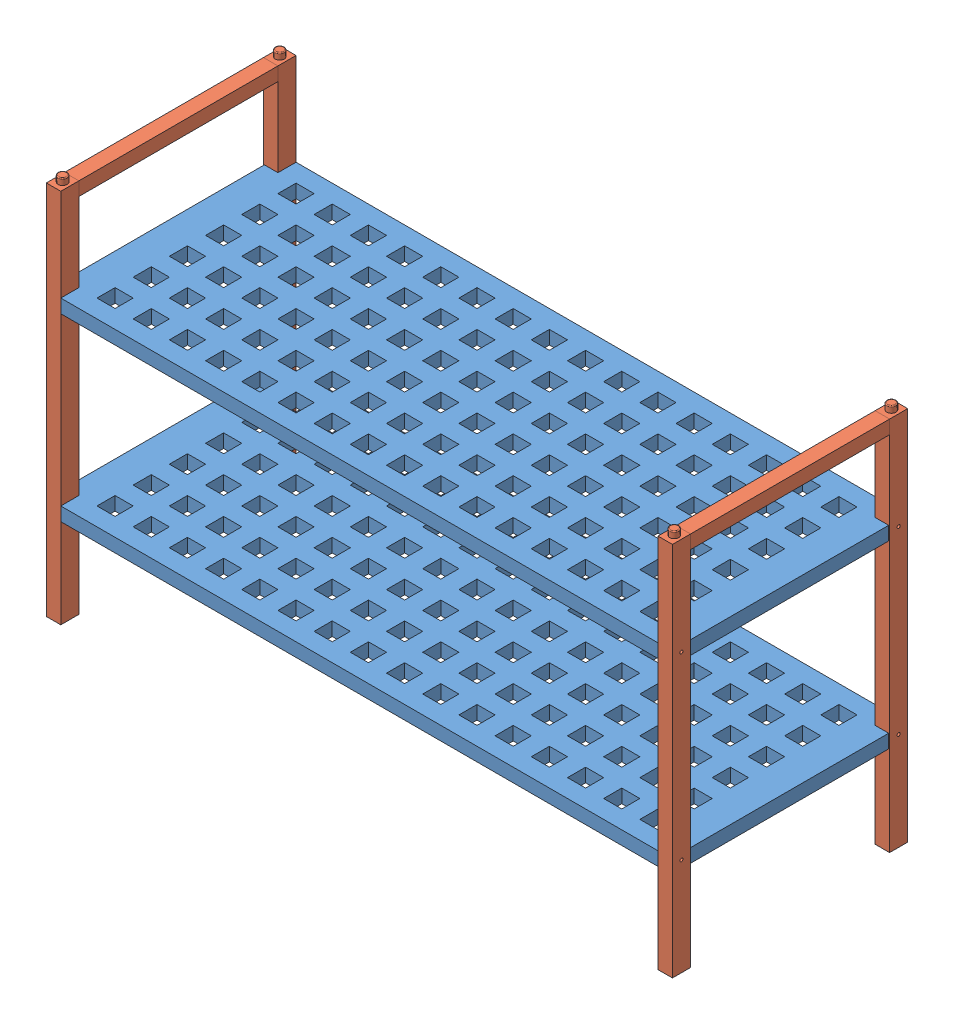
SolidWorks assembly Shoe Rack Assembly - Homework 2, configuration Default. Lengths in mm.
Overall size (692 422 260).
4 component instances, 2 part files, 13 mates.
Components (placement in the parent):
- Shoe Rack Plate - Homework 2-1: Shoe Rack Plate - Homework 2 [Default] at origin size (690 15 260)
- Shoe Rack End - Homework 2-2: Shoe Rack End - Homework 2 [Default] at (-374.3767 -95.0019 -133.8437) x (0 0 1) z (-1 0 0) size (260 422 16)
- Shoe Rack End - Homework 2-3: Shoe Rack End - Homework 2 [Default] at (317.6233 -95.0019 86.1563) x (0 0 -1) z (1 0 0) size (260 422 16)
- Shoe Rack Plate - Homework 2-4: Shoe Rack Plate - Homework 2 [Default] at (0 -199 0) size (690 15 260)
Mates (geometry in assembly coordinates):
- Coincident6: coincident anti-aligned: plane of Shoe Rack Plate - Homework 2-1 through (-358.3767 -15 -133.8437) normal (-1 0 0); plane of Shoe Rack End - Homework 2-2 through (-358.3767 -312.8 -153.8437) normal (1 0 0)
- Coincident7: coincident anti-aligned: plane of Shoe Rack Plate - Homework 2-1 through (-373.3767 -15 -133.8437) normal (0 0 -1); plane of Shoe Rack End - Homework 2-2 through (-374.3767 -95.0019 -133.8437) normal (0 0 1)
- Coincident8: coincident: circle of assembly; point of Shoe Rack Plate - Homework 2-1; circle of Shoe Rack End - Homework 2-2
- Coincident10: coincident anti-aligned: plane of Shoe Rack Plate - Homework 2-1 through (301.6233 -15 86.1563) normal (1 0 0); plane of Shoe Rack End - Homework 2-3 through (301.6233 -312.8 106.1563) normal (-1 0 0)
- Coincident11: coincident anti-aligned: plane of Shoe Rack Plate - Homework 2-1 through (316.6233 -15 86.1563) normal (0 0 1); plane of Shoe Rack End - Homework 2-3 through (317.6233 -95.0019 86.1563) normal (0 0 -1)
- Coincident12: coincident: circle of assembly; point of Shoe Rack Plate - Homework 2-1; circle of Shoe Rack End - Homework 2-3
- Coincident14: coincident anti-aligned: plane of Shoe Rack End - Homework 2-2 through (-358.3767 -312.8 106.1563) normal (1 0 0); plane of Shoe Rack Plate - Homework 2-4 through (-358.3767 -214 106.1563) normal (-1 0 0)
- Coincident15: coincident anti-aligned: plane of Shoe Rack End - Homework 2-2 through (-374.3767 -95.0019 86.1563) normal (0 0 -1); plane of Shoe Rack Plate - Homework 2-4 through (-358.3767 -214 86.1563) normal (0 0 1)
- Coincident16: coincident: circle of Shoe Rack End - Homework 2-2
- Coincident17: coincident: circle of assembly; point of Shoe Rack Plate - Homework 2-1; circle of Shoe Rack End - Homework 2-2
- Coincident18: coincident: circle of Shoe Rack End - Homework 2-2
- Coincident19: coincident: circle of assembly; point of Shoe Rack Plate - Homework 2-1; circle of Shoe Rack End - Homework 2-2
- Coincident20: coincident: circle of Shoe Rack End - Homework 2-2
